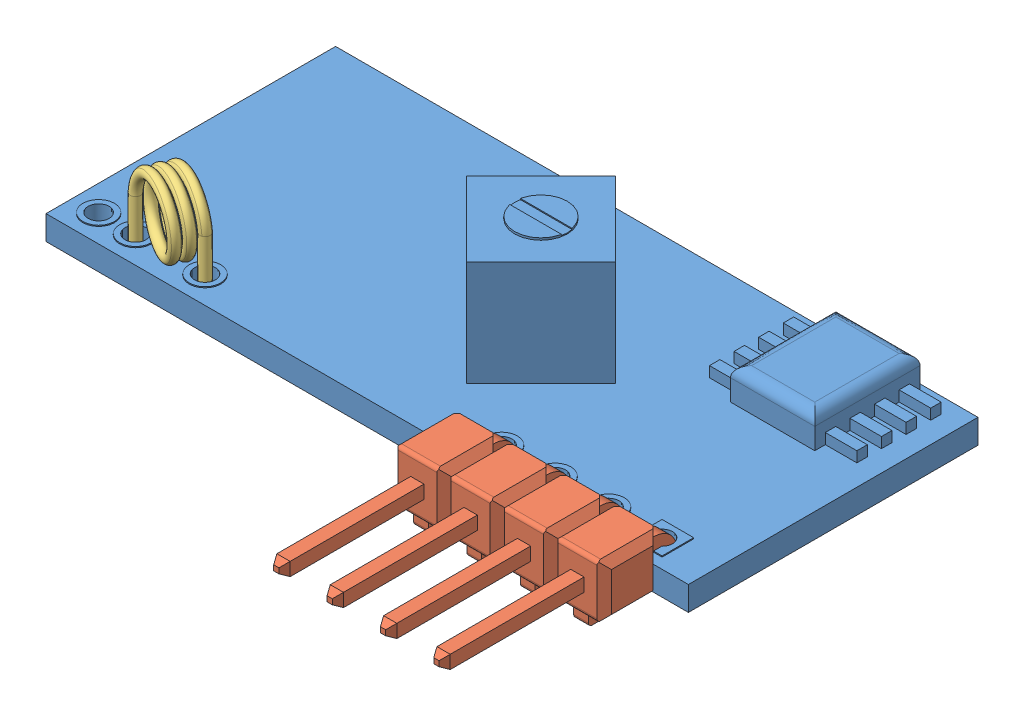
SolidWorks assembly Receiver, configuration Default. Lengths in mm.
Overall size (30.5 6.76 23.25).
3 component instances, 3 part files, 7 mates.
Components (placement in the parent):
- pcb-1: pcb [Default] at (12.598 14.3931 23.8062) size (30.5 6.3 13.75)
- Pin Header 1x4 TH Angle Pitch 2.54mm.stp-1: Pin Header 1x4 TH Angle Pitch 2.54mm.stp [Default] at (10.3745 14.0381 34.9929) x (0.999997 0 0.0026) z (0 1 0) size (10.17 11.16 6.3)
- small coil v1.stp-1: small coil v1.stp [Default] at (-17.1654 14.2931 51.3212) x (0.937425 0 -0.348187) z (0.348187 0 0.937425) size (3.59 4.14 3.27)
Mates (geometry in assembly coordinates):
- Parallel3: parallel: plane of pcb-1 through (12.598 15.5431 23.8062) normal (0 1 0); plane of Pin Header 1x4 TH Angle Pitch 2.54mm.stp-1 through (11.3175 17.1281 36.2664) normal (0 1 0)
- Distance1: distance = 1.2 mm: plane of pcb-1 through (20.4645 15.5431 22.5642) normal (1 0 0); plane of Pin Header 1x4 TH Angle Pitch 2.54mm.stp-1 through (19.2645 16.8011 38.7869) normal (1 0 0)
- Coincident4: coincident: plane of pcb-1 through (12.598 15.5431 23.8062) normal (0 1 0); moEndPointRef_w of Pin Header 1x4 TH Angle Pitch 2.54mm.stp-1
- Coincident5: coincident: plane of pcb-1 through (-10.0355 15.5431 36.3142) normal (0 0 1); plane of Pin Header 1x4 TH Angle Pitch 2.54mm.stp-1 through (18.7915 14.5781 36.3142) normal (0 0 -1)
- Concentric1: concentric: cylinder of pcb-1 through (-3.7355 14.3431 35.0642) axis (0 1 0) radius 0.5; cylinder of small coil v1.stp-1 through (-3.7355 -499985.7069 35.0642) axis (0 1 0) radius 0.25
- Concentric2: concentric: cylinder of pcb-1 through (-7.0355 14.3431 35.0642) axis (0 1 0) radius 0.5; cylinder of small coil v1.stp-1 through (-7.0356 -499985.7069 35.0642) axis (0 1 0) radius 0.25
- Tangent3: tangent: plane of pcb-1 through (12.598 15.5431 23.8062) normal (0 1 0); face of small coil v1.stp-1
